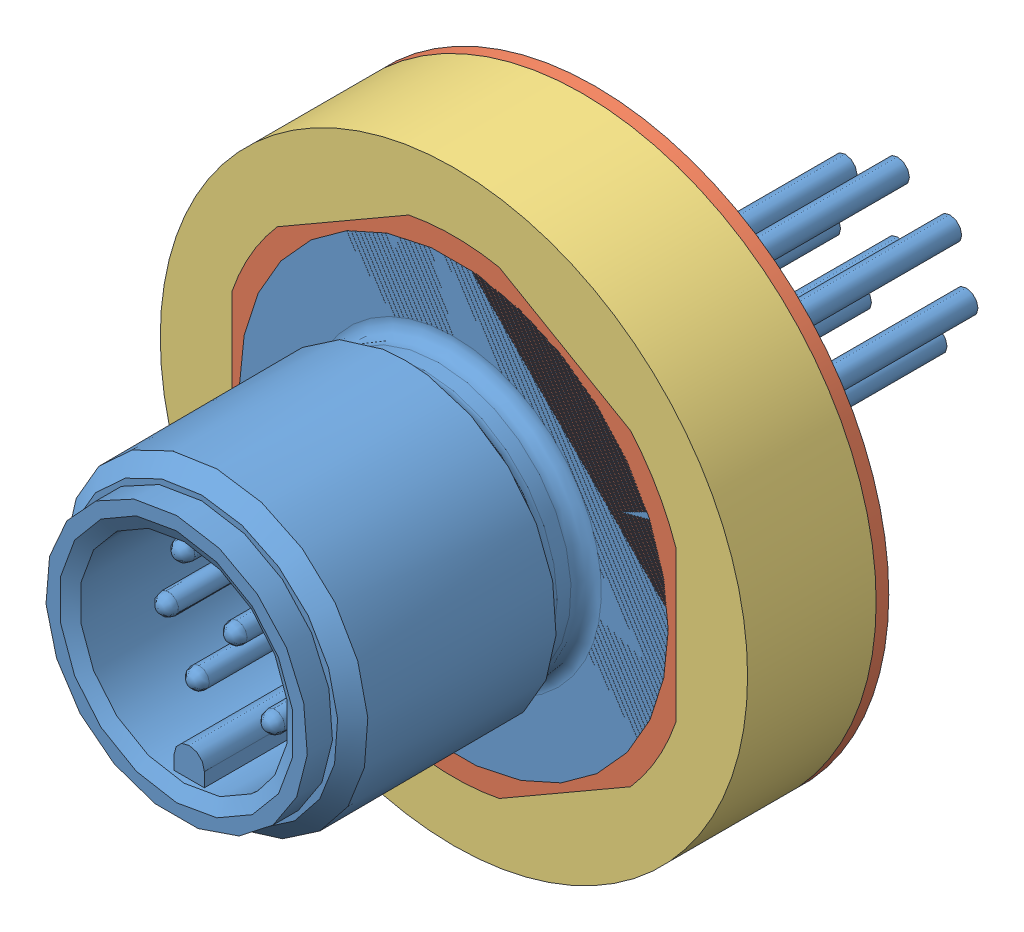
SolidWorks assembly panelMountM12Connector, configuration Default. Lengths in mm.
Overall size (22.1 22.1 28.6).
4 component instances, 4 part files, 6 mates.
Components (placement in the parent):
- 76_2131_0111_00008-1: 76_2131_0111_00008 [Default] at (0 0 10) x (0 0 -1) z (0 -1 0) size (28.6 17.02 18)
- guaranteedEmbedmentTool^panelMountM12Connector-1: guaranteedEmbedmentTool^panelMountM12Connector [Default] at origin size (22.1 22.1 5.1) (hidden, virtual)
- panelSubtraction^panelMountM12Connector-1: panelSubtraction^panelMountM12Connector [Default] at origin size (22.1 22.1 5.6) (virtual)
- panelAddition^panelMountM12Connector-1: panelAddition^panelMountM12Connector [Default] at origin size (22.1 22.1 5.1) (virtual)
Mates (geometry in assembly coordinates):
- Coincident5: coordinate: point of ?
- Coincident6: coincident: point of 76_2131_0111_00008-1; line of assembly
- connectorIsSunkIntoPanel: distance aligned: plane of 76_2131_0111_00008-1 through (0 0 -2) normal (0 0 1); plane of assembly through (0 0 0) normal (0 0 1)
- Parallel1: parallel aligned: line of 76_2131_0111_00008-1 through (-50 0 10) axis (1 0 0); line of assembly
- Coincident8: coordinate: unknown of ?
- Coincident9: coordinate: unknown of ?
